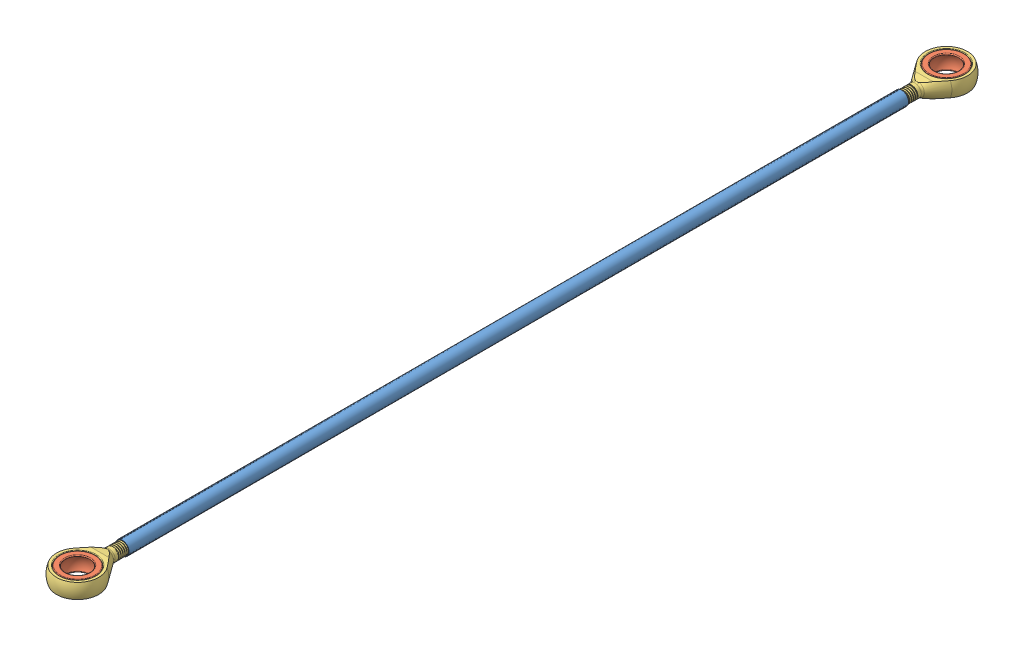
SolidWorks assembly SubTayDuoi, configuration Default. Lengths in mm.
Overall size (18 6.77 368).
5 component instances, 3 part files, 7 mates.
Components (placement in the parent):
- TayDuoi-1: TayDuoi [Default] at (122.3807 165.3749 80.2646) size (5.5 5.5 314)
- Ball Washer-1: Ball Washer [M5*0.8] at (122.3807 165.3749 62.2646) x (-1 0 0) z (0 0 1) size (14.4 6 14.4)
- Male Rod End Bearing-1: Male Rod End Bearing [M5*0.8] at (122.3807 165.3749 62.2646) x (0 0 1) z (1 0 0) size (42.16 6.77 18)
- Ball Washer-2: Ball Washer [M5*0.8] at (122.3807 165.3749 412.2646) size (14.4 6 14.4)
- Male Rod End Bearing-2: Male Rod End Bearing [M5*0.8] at (122.3807 165.3749 412.2646) x (0 0 -1) z (1 0 0) size (42.16 6.77 18)
Mates (geometry in assembly coordinates):
- Concentric1: concentric aligned: circle of Ball Washer-1; circle of Male Rod End Bearing-1
- Coincident1: coincident aligned: plane of Ball Washer-1 through (119.2112 160.8128 62.2646) normal (0.383049 -0.923728 0); plane of Male Rod End Bearing-1 through (123.5298 162.6037 69.4646) normal (0.383049 -0.923728 0)
- Concentric2: concentric aligned: circle of Ball Washer-2; circle of Male Rod End Bearing-2
- Coincident2: coincident aligned: plane of Ball Washer-2 through (127.056 168.3749 412.2646) normal (0 1 0); plane of Male Rod End Bearing-2 through (119.7614 167.2451 121.3862) normal (0 1 0)
- ProfileCenter1: profile center = 15 mm: circle of Male Rod End Bearing-1; circle of TayDuoi-1
- ProfileCenter2: profile center = 15 mm: plane of Male Rod End Bearing-2 through (122.3807 165.3749 379.2646) normal (0 0 -1); circle of TayDuoi-1
- Coincident3: coincident aligned: plane of Male Rod End Bearing-1 through (122.3807 168.3749 69.4646) normal (0 1 0); plane of Male Rod End Bearing-2 through (122.3807 168.3749 405.0646) normal (0 1 0)
